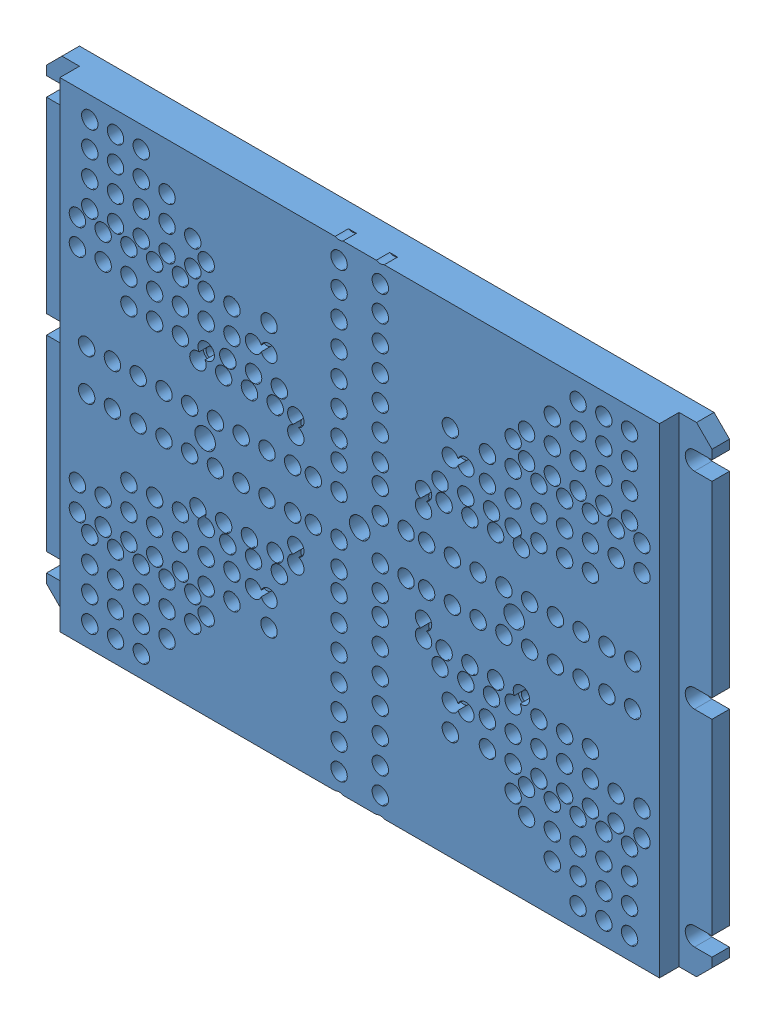
SolidWorks assembly H1000 C755 v1, configuration Défaut. Lengths in mm.
Overall size (646 466 36).
2 component instances, 1 part files, 0 mates.
Components (placement in the parent):
- H1000 C755 v1(2)^H1000 C755-1: H1000 C755 v1(2)^H1000 C755 [Défaut] at origin size (646 466 36) (virtual)
  - ^H1000 C755 v1(2)_H1000 C755-1: ^H1000 C755 v1(2)_H1000 C755 [Défaut] at (300.28 -179.29 -250) size (646 466 36) (virtual)
